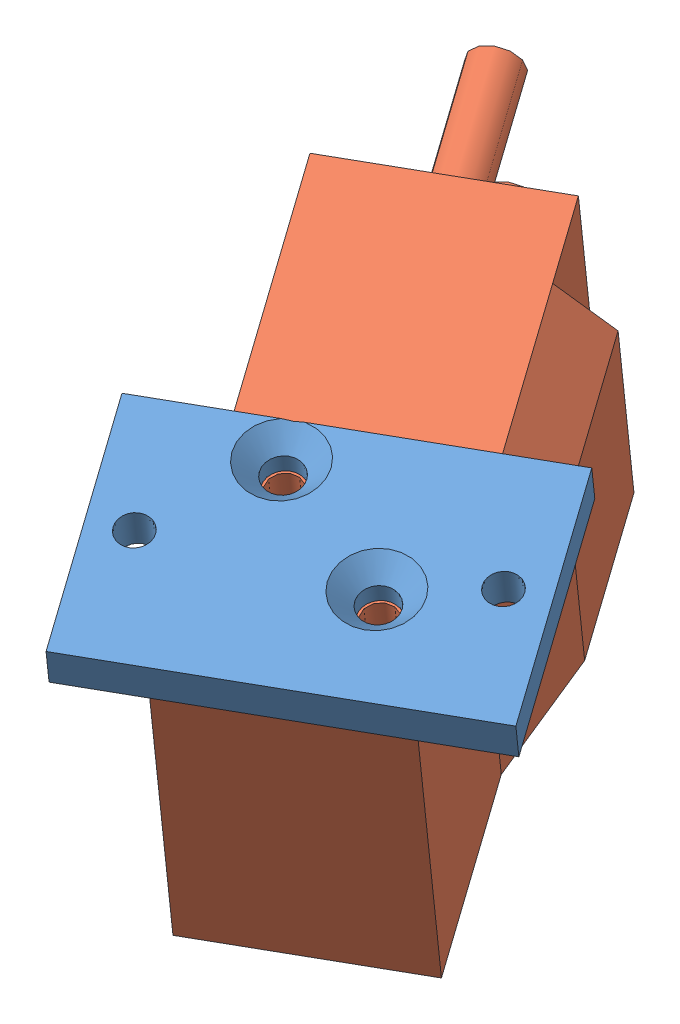
SolidWorks assembly C1 Contactor, configuration Default. Lengths in mm.
Overall size (77.16 61.68 98.73).
2 component instances, 2 part files, 3 mates.
Components (placement in the parent):
- C1 Mount Plate-1: C1 Mount Plate [Default] at (15.3973 8.1357 68.583) x (0.85542 -0.020058 -0.517547) z (0.484974 -0.319759 0.813974) size (44.45 4.97 29.97)
- C1 Relay-1: C1 Relay [Default] at (-7.1274 28.1682 12.1728) x (0.484974 -0.319759 0.813974) z (0.85542 -0.020058 -0.517547) size (81.83 36.83 31.24)
Mates (geometry in assembly coordinates):
- Concentric1: concentric aligned: circle of C1 Mount Plate-1; circle of C1 Relay-1
- Coincident3: coincident anti-aligned: plane of C1 Mount Plate-1 through (0.8617 17.7196 44.1866) normal (-0.181817 -0.947286 -0.263801); plane of C1 Relay-1 through (14.6002 27.6587 -0.9729) normal (0.181817 0.947286 0.263801)
- Concentric2: concentric aligned: circle of C1 Mount Plate-1; circle of C1 Relay-1
